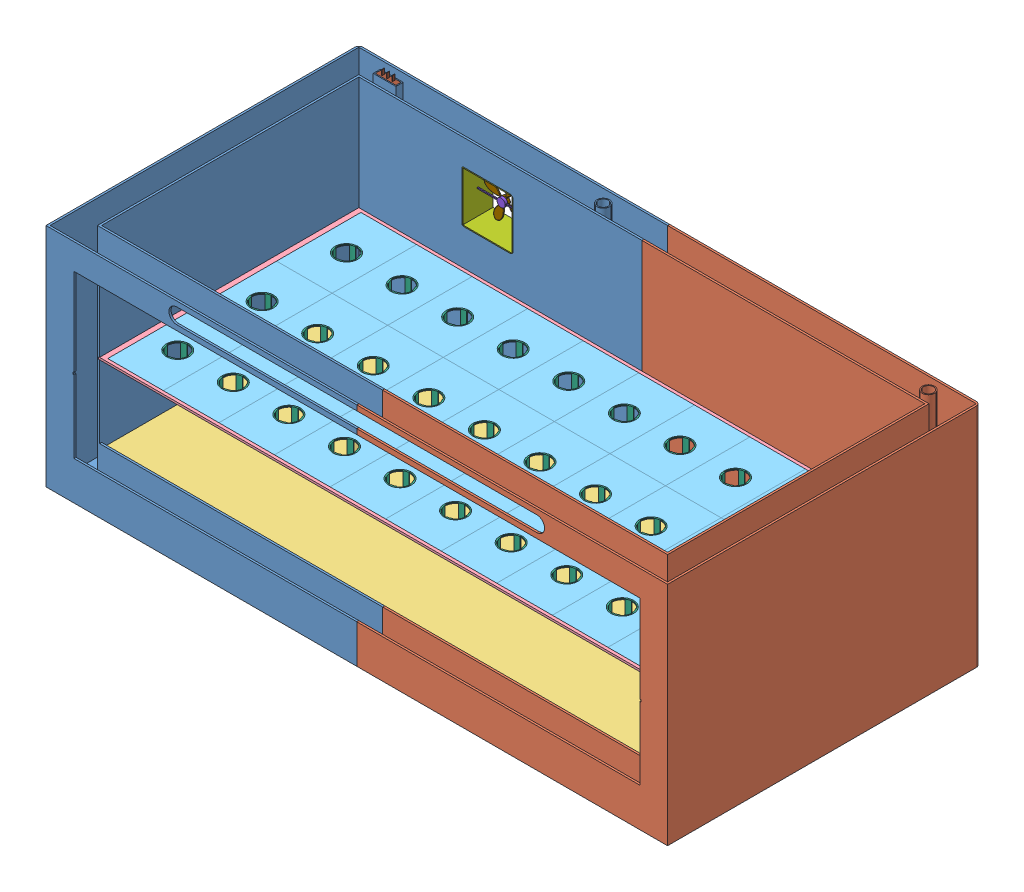
SolidWorks assembly A_Modulo, configuration Default. Lengths in mm.
Overall size (1208 450 613).
71 component instances, 11 part files, 16 mates.
Components (placement in the parent):
- Modulo_Peca1-1: Modulo_Peca1 [Default] at (151.1194 215.8381 575.6302) size (604 440 608)
- Modulo_Peca2-2: Modulo_Peca2 [Default] at (151.1194 215.8381 575.6302) x (-1 0 0) z (0 0 -1) size (644 440 608)
- Placas_divisao_modulo-3: Placas_divisao_modulo [Default] at (151.1194 278.8381 575.6302) size (1104 77 504)
- A_Gaveta-3: A_Gaveta [Default] at (-1.3006 -541.9592 64.8858) size (1104 41 504.01)
  - Estrutura_gaveta-2: Estrutura_gaveta [Default] at (152.42 973.7974 512.7504) size (1104 4 504.01)
  - Copo_cultura-81: Copo_cultura [Default] at (-333.58 977.7974 348.7504) size (108 2 164)
  - Copo_cultura-82: Copo_cultura [Default] at (-225.58 977.7974 348.7504) size (108 2 164)
  - Copo_cultura-83: Copo_cultura [Default] at (-117.58 977.7974 348.7504) size (108 2 164)
  - Copo_cultura-84: Copo_cultura [Default] at (-9.58 977.7974 348.7504) size (108 2 164)
  - Copo_cultura-85: Copo_cultura [Default] at (98.42 977.7974 348.7504) size (108 2 164)
  - Copo_cultura-86: Copo_cultura [Default] at (206.42 977.7974 348.7504) size (108 2 164)
  - Copo_cultura-87: Copo_cultura [Default] at (314.42 977.7974 348.7504) size (108 2 164)
  - Copo_cultura-88: Copo_cultura [Default] at (422.42 977.7974 348.7504) size (108 2 164)
  - Copo_cultura-89: Copo_cultura [Default] at (530.42 977.7974 348.7504) size (108 2 164)
  - Copo_cultura-90: Copo_cultura [Default] at (638.42 977.7974 348.7504) size (108 2 164)
  - Copo_cultura-91: Copo_cultura [Default] at (-333.58 977.7974 512.7504) size (108 2 164)
  - Copo_cultura-92: Copo_cultura [Default] at (-333.58 977.7974 676.7504) size (108 2 164)
  - Copo_cultura-93: Copo_cultura [Default] at (-225.58 977.7974 512.7504) size (108 2 164)
  - Copo_cultura-94: Copo_cultura [Default] at (-225.58 977.7974 676.7504) size (108 2 164)
  - Copo_cultura-95: Copo_cultura [Default] at (-117.58 977.7974 512.7504) size (108 2 164)
  - Copo_cultura-96: Copo_cultura [Default] at (-117.58 977.7974 676.7504) size (108 2 164)
  - Copo_cultura-97: Copo_cultura [Default] at (-9.58 977.7974 512.7504) size (108 2 164)
  - Copo_cultura-98: Copo_cultura [Default] at (-9.58 977.7974 676.7504) size (108 2 164)
  - Copo_cultura-99: Copo_cultura [Default] at (98.42 977.7974 512.7504) size (108 2 164)
  - Copo_cultura-100: Copo_cultura [Default] at (98.42 977.7974 676.7504) size (108 2 164)
  - Copo_cultura-101: Copo_cultura [Default] at (206.42 977.7974 512.7504) size (108 2 164)
  - Copo_cultura-102: Copo_cultura [Default] at (206.42 977.7974 676.7504) size (108 2 164)
  - Copo_cultura-103: Copo_cultura [Default] at (314.42 977.7974 512.7504) size (108 2 164)
  - Copo_cultura-104: Copo_cultura [Default] at (314.42 977.7974 676.7504) size (108 2 164)
  - Copo_cultura-105: Copo_cultura [Default] at (422.42 977.7974 512.7504) size (108 2 164)
  - Copo_cultura-106: Copo_cultura [Default] at (422.42 977.7974 676.7504) size (108 2 164)
  - Copo_cultura-107: Copo_cultura [Default] at (530.42 977.7974 512.7504) size (108 2 164)
  - Copo_cultura-108: Copo_cultura [Default] at (530.42 977.7974 676.7504) size (108 2 164)
  - Copo_cultura-109: Copo_cultura [Default] at (638.42 977.7974 512.7504) size (108 2 164)
  - Copo_cultura-110: Copo_cultura [Default] at (638.42 977.7974 676.7504) size (108 2 164)
  - Capsula_Cultura-1: Capsula_Cultura [Default] at (-333.58 976.7974 676.7504) x (0.947711 0 -0.319129) z (0.319129 0 0.947711) size (44 41 44)
  - Capsula_Cultura-2: Capsula_Cultura [Default] at (-225.58 976.7974 676.7504) x (0.947711 0 -0.319129) z (0.319129 0 0.947711) size (44 41 44)
  - Capsula_Cultura-3: Capsula_Cultura [Default] at (-117.58 976.7974 676.7504) x (0.947711 0 -0.319129) z (0.319129 0 0.947711) size (44 41 44)
  - Capsula_Cultura-4: Capsula_Cultura [Default] at (-9.58 976.7974 676.7504) x (0.947711 0 -0.319129) z (0.319129 0 0.947711) size (44 41 44)
  - Capsula_Cultura-5: Capsula_Cultura [Default] at (98.42 976.7974 676.7504) x (0.947711 0 -0.319129) z (0.319129 0 0.947711) size (44 41 44)
  - Capsula_Cultura-6: Capsula_Cultura [Default] at (206.42 976.7974 676.7504) x (0.947711 0 -0.319129) z (0.319129 0 0.947711) size (44 41 44)
  - Capsula_Cultura-7: Capsula_Cultura [Default] at (314.42 976.7974 676.7504) x (0.947711 0 -0.319129) z (0.319129 0 0.947711) size (44 41 44)
  - Capsula_Cultura-8: Capsula_Cultura [Default] at (422.42 976.7974 676.7504) x (0.947711 0 -0.319129) z (0.319129 0 0.947711) size (44 41 44)
  - Capsula_Cultura-9: Capsula_Cultura [Default] at (530.42 976.7974 676.7504) x (0.947711 0 -0.319129) z (0.319129 0 0.947711) size (44 41 44)
  - Capsula_Cultura-10: Capsula_Cultura [Default] at (638.42 976.7974 676.7504) x (0.947711 0 -0.319129) z (0.319129 0 0.947711) size (44 41 44)
  - Capsula_Cultura-11: Capsula_Cultura [Default] at (-333.58 976.7974 512.7504) x (0.947711 0 -0.319129) z (0.319129 0 0.947711) size (44 41 44)
  - Capsula_Cultura-12: Capsula_Cultura [Default] at (-333.58 976.7974 348.7504) x (0.947711 0 -0.319129) z (0.319129 0 0.947711) size (44 41 44)
  - Capsula_Cultura-13: Capsula_Cultura [Default] at (-225.58 976.7974 512.7504) x (0.947711 0 -0.319129) z (0.319129 0 0.947711) size (44 41 44)
  - Capsula_Cultura-14: Capsula_Cultura [Default] at (-225.58 976.7974 348.7504) x (0.947711 0 -0.319129) z (0.319129 0 0.947711) size (44 41 44)
  - Capsula_Cultura-15: Capsula_Cultura [Default] at (-117.58 976.7974 512.7504) x (0.947711 0 -0.319129) z (0.319129 0 0.947711) size (44 41 44)
  - Capsula_Cultura-16: Capsula_Cultura [Default] at (-117.58 976.7974 348.7504) x (0.947711 0 -0.319129) z (0.319129 0 0.947711) size (44 41 44)
  - Capsula_Cultura-17: Capsula_Cultura [Default] at (-9.58 976.7974 512.7504) x (0.947711 0 -0.319129) z (0.319129 0 0.947711) size (44 41 44)
  - Capsula_Cultura-18: Capsula_Cultura [Default] at (-9.58 976.7974 348.7504) x (0.947711 0 -0.319129) z (0.319129 0 0.947711) size (44 41 44)
  - Capsula_Cultura-19: Capsula_Cultura [Default] at (98.42 976.7974 512.7504) x (0.947711 0 -0.319129) z (0.319129 0 0.947711) size (44 41 44)
  - Capsula_Cultura-20: Capsula_Cultura [Default] at (98.42 976.7974 348.7504) x (0.947711 0 -0.319129) z (0.319129 0 0.947711) size (44 41 44)
  - Capsula_Cultura-21: Capsula_Cultura [Default] at (206.42 976.7974 512.7504) x (0.947711 0 -0.319129) z (0.319129 0 0.947711) size (44 41 44)
  - Capsula_Cultura-22: Capsula_Cultura [Default] at (206.42 976.7974 348.7504) x (0.947711 0 -0.319129) z (0.319129 0 0.947711) size (44 41 44)
  - Capsula_Cultura-23: Capsula_Cultura [Default] at (314.42 976.7974 512.7504) x (0.947711 0 -0.319129) z (0.319129 0 0.947711) size (44 41 44)
  - Capsula_Cultura-24: Capsula_Cultura [Default] at (314.42 976.7974 348.7504) x (0.947711 0 -0.319129) z (0.319129 0 0.947711) size (44 41 44)
  - Capsula_Cultura-25: Capsula_Cultura [Default] at (422.42 976.7974 512.7504) x (0.947711 0 -0.319129) z (0.319129 0 0.947711) size (44 41 44)
  - Capsula_Cultura-26: Capsula_Cultura [Default] at (422.42 976.7974 348.7504) x (0.947711 0 -0.319129) z (0.319129 0 0.947711) size (44 41 44)
  - Capsula_Cultura-27: Capsula_Cultura [Default] at (530.42 976.7974 512.7504) x (0.947711 0 -0.319129) z (0.319129 0 0.947711) size (44 41 44)
  - Capsula_Cultura-28: Capsula_Cultura [Default] at (530.42 976.7974 348.7504) x (0.947711 0 -0.319129) z (0.319129 0 0.947711) size (44 41 44)
  - Capsula_Cultura-29: Capsula_Cultura [Default] at (638.42 976.7974 512.7504) x (0.947711 0 -0.319129) z (0.319129 0 0.947711) size (44 41 44)
  - Capsula_Cultura-30: Capsula_Cultura [Default] at (638.42 976.7974 348.7504) x (0.947711 0 -0.319129) z (0.319129 0 0.947711) size (44 41 44)
- A_Ventilador-1: A_Ventilador [Default] at (-143.7426 484.8829 374.0047) x (-1 0 0) z (0 0 -1) size (121.7 121.7 59)
  - CasingVentilador-1: CasingVentilador [Default] at (5.1379 70.9552 107.3745) size (120 120 59)
  - LigacaoFan_Casing-1: LigacaoFan_Casing [Default] at (5.1379 70.9552 74.8745) size (96 16 5)
  - Fan-1: Fan [Default] at (5.1379 70.9552 79.8745) x (-0.915029 -0.403389 0) z (0 0 1) size (92.31 92.31 5)
- Tubo_injeccao_agua-2: Tubo_injeccao_agua [Default] at (643.0083 300.8381 325.6302) size (818.93 24.03 249.8)
- Tubagem_electricidade-1: Tubagem_electricidade [Default] at (-368.8806 215.8381 298.6302) size (40 450 10)
Mates (geometry in assembly coordinates):
- Coincident7: coincident: plane of Modulo_Peca1-1 through (151.1194 655.8381 271.6302) normal (1 0 0); plane of Modulo_Peca2-2 through (151.1194 655.8381 275.6302) normal (-1 0 0)
- Coincident8: coincident: point of Modulo_Peca1-1; point of Modulo_Peca2-2
- Coincident9: coincident: point of Modulo_Peca1-1; point of Modulo_Peca2-2
- Coincident12: coincident: line of Modulo_Peca1-1 through (-400.8806 280.8381 827.6302) axis (1 0 0); line of Placas_divisao_modulo-3 through (-400.8806 280.8381 827.6302) axis (1 0 0)
- Coincident27: coincident: line of Modulo_Peca1-1 through (-400.8806 435.8381 325.6302) axis (0 0 1); line of A_Gaveta-3/Estrutura_gaveta-2 through (-400.8806 435.8381 829.6423) axis (0 0 -1)
- Parallel4: parallel: plane of Modulo_Peca1-1 through (-398.8806 290.8381 825.6302) normal (0 1 0); line of A_Gaveta-3/Estrutura_gaveta-2 through (-400.8806 431.8381 829.6423) axis (1 0 0)
- Coincident29: coincident: plane of Modulo_Peca2-2 through (701.1194 655.8381 325.6302) normal (0 0 1); plane of A_Gaveta-3/Estrutura_gaveta-2 through (-400.8806 435.8381 325.6302) normal (0 0 -1)
- Coincident30: coincident: line of Modulo_Peca1-1 through (-98.8806 512.8381 325.6302) axis (0 1 0); line of A_Ventilador-1/CasingVentilador-1 through (-98.8806 509.8381 325.6302) axis (0 1 0)
- Coincident31: coincident: line of Modulo_Peca1-1 through (-198.8806 512.8381 325.6302) axis (0 1 0); line of A_Ventilador-1/CasingVentilador-1 through (-198.8806 509.8381 325.6302) axis (0 1 0)
- Coincident32: coincident: plane of Modulo_Peca1-1 through (-198.8806 505.8381 271.6302) normal (0 1 0); plane of A_Ventilador-1/CasingVentilador-1 through (-98.8806 505.8381 325.6302) normal (0 -1 0)
- Coincident35: coincident: circle of Modulo_Peca2-2; circle of Tubo_injeccao_agua-2
- Coincident36: coincident: plane of Modulo_Peca1-1 through (-388.8806 209.8381 303.6302) normal (0 0 -1); plane of Tubagem_electricidade-1 through (-388.8806 655.8381 303.6302) normal (0 0 1)
- Coincident37: coincident: moEndPointRef_w of Modulo_Peca1-1; line of Tubagem_electricidade-1 through (-388.8806 655.8381 293.6302) axis (0 0 1)
- Coincident38: coincident: point of Modulo_Peca1-1; line of Tubagem_electricidade-1 through (-348.8806 655.8381 303.6302) axis (0 0 -1)
- Coincident39: coincident: line of Modulo_Peca1-1 through (151.1194 280.8381 323.6302) axis (-1 0 0); line of Placas_divisao_modulo-3 through (703.1194 280.8381 323.6302) axis (-1 0 0)
- Coincident40: coincident: plane of Modulo_Peca1-1 through (-400.8806 280.8381 323.6302) normal (1 0 0); line of Placas_divisao_modulo-3 through (-400.8806 280.8381 323.6302) axis (0 0 1)
